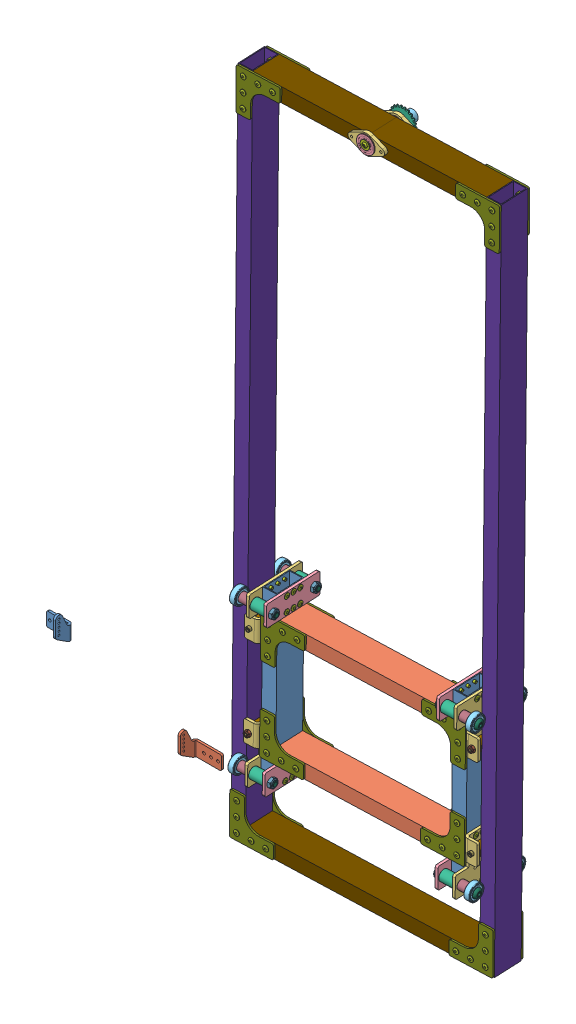
SolidWorks assembly Elevator Assembly, configuration Default. Lengths in mm.
Overall size (536.25 1232.63 399.07).
260 component instances, 26 part files, 13 mates.
Components (placement in the parent):
- Left Carriage Chain Mount-1: Left Carriage Chain Mount [Default] at (-1.4797 21.5105 53.1771) size (44.45 50.8 31.75)
- Right Carriage Chain Mount-1: Right Carriage Chain Mount [Default] at (172.2873 -143.217 -42.9173) size (50.8 50.8 31.75)
- am-3844a Example Single Stage Elevator Bearing Kit (1).STEP-1: am-3844a Example Single Stage Elevator Bearing Kit (1).STEP [Default] at (43.0927 -420.3455 -214.8461) x (0.998923 -0.01032 -0.045245) z (0.045242 -0.000545 0.998976) size (457.2 1219.2 116.33)
  - Example Single Corner Bearing Assembly R2.STEP-1: Example Single Corner Bearing Assembly R2.STEP [Default] at (14.8715 309.5253 9.4128) x (0 0 1) z (-1 0 0) size (112.43 88.9 74.91)
    - Large Bearing Block Plate R2.STEP-1: Large Bearing Block Plate R2.STEP [Default] at (-85.6128 70.3392 -35.9285) x (1 0 0) z (0 -1 0) size (101.6 24.99 88.9)
    - Small Bearing Block Plate R2.STEP-1: Small Bearing Block Plate R2.STEP [Default] at (-85.6128 70.3392 -66.091) x (1 0 0) z (0 -1 0) size (101.6 4.76 38.1)
    - 1614Z Bearing.STEP-1: 1614Z Bearing.STEP [Default] at (-74.6273 89.3892 -8.941) x (0.346238 -0.938147 0) z (0 0 1) size (28.57 28.57 9.53)
    - 1614Z Bearing.STEP-2: 1614Z Bearing.STEP [Default] at (5.0017 89.3892 -8.941) x (0.999932 0.011696 0) z (0 0 1) size (28.57 28.57 9.53)
    - AS75-18-64 Aluminum Spacer.STEP-1: AS75-18-64 Aluminum Spacer.STEP [Default] at (5.0017 89.3892 -35.9285) x (-0.078952 0.996878 0) z (-0.996878 -0.078952 0) size (19.05 25.4 19.05)
    - AS75-18-64 Aluminum Spacer.STEP-2: AS75-18-64 Aluminum Spacer.STEP [Default] at (-74.6273 89.3892 -61.3285) x (-0.205985 0.978555 0) z (0.978555 0.205985 0) size (19.05 25.4 19.05)
    - 187 pop rivet.STEP-1: 187 pop rivet.STEP [Default] at (-22.1128 102.0892 -41.707) x (0.970848 -0.239695 0) z (-0.239695 -0.970848 0) size (9.53 12.06 9.53)
    - 187 pop rivet.STEP-2: 187 pop rivet.STEP [Default] at (-22.1128 102.0892 -55.55) x (1 0 0) z (0 1 0) size (9.53 12.06 9.53)
    - 187 pop rivet.STEP-3: 187 pop rivet.STEP [Default] at (-34.8128 102.0892 -41.707) x (0.970848 -0.239695 0) z (-0.239695 -0.970848 0) size (9.53 12.06 9.53)
    - 187 pop rivet.STEP-4: 187 pop rivet.STEP [Default] at (-47.5128 102.0892 -41.707) x (0.970848 -0.239695 0) z (-0.239695 -0.970848 0) size (9.53 12.06 9.53)
    - 187 pop rivet.STEP-5: 187 pop rivet.STEP [Default] at (-22.1128 25.8892 -41.707) x (0.970848 -0.239695 0) z (-0.239695 -0.970848 0) size (9.53 12.06 9.53)
    - 187 pop rivet.STEP-6: 187 pop rivet.STEP [Default] at (-34.8128 25.8892 -41.707) x (0.970848 -0.239695 0) z (-0.239695 -0.970848 0) size (9.53 12.06 9.53)
    - 187 pop rivet.STEP-7: 187 pop rivet.STEP [Default] at (-47.5128 25.8892 -41.707) x (0.970848 -0.239695 0) z (-0.239695 -0.970848 0) size (9.53 12.06 9.53)
    - 187 pop rivet.STEP-8: 187 pop rivet.STEP [Default] at (-22.1128 76.6892 -55.55) x (1 0 0) z (0 1 0) size (9.53 12.06 9.53)
    - 187 pop rivet.STEP-9: 187 pop rivet.STEP [Default] at (-34.8128 102.0892 -55.55) x (1 0 0) z (0 1 0) size (9.53 12.06 9.53)
    - 187 pop rivet.STEP-10: 187 pop rivet.STEP [Default] at (-34.8128 76.6892 -55.55) x (1 0 0) z (0 1 0) size (9.53 12.06 9.53)
    - 187 pop rivet.STEP-11: 187 pop rivet.STEP [Default] at (-47.5128 102.0892 -55.55) x (1 0 0) z (0 1 0) size (9.53 12.06 9.53)
    - 187 pop rivet.STEP-12: 187 pop rivet.STEP [Default] at (-47.5128 76.6892 -55.55) x (1 0 0) z (0 1 0) size (9.53 12.06 9.53)
    - am-0602 .250 x .192 x 2.14 Brass Tube.STEP-1: am-0602 .250 x .192 x 2.14 Brass Tube.STEP [Default] at (-7.6348 38.5892 -20.0535) x (0 -0.358682 0.93346) z (-1 0 0) size (6.35 6.35 54.36)
    - 13RS075051 .750 x .260 x 1.00 Spacer.STEP-1: 13RS075051 .750 x .260 x 1.00 Spacer.STEP [Default] at (-60.2128 38.5892 -20.0535) x (0 -0.722855 0.691) z (0 0.691 0.722855) size (19.05 25.4 19.05)
    - 13RS075051 .750 x .260 x 1.00 Spacer.STEP-2: 13RS075051 .750 x .260 x 1.00 Spacer.STEP [Default] at (-34.8128 38.5892 -20.0535) x (0 -0.801304 -0.598258) z (0 -0.598258 0.801304) size (19.05 25.4 19.05)
    - 0.25 Flat Washer_Preferred Wide FW 0.25.STEP-1: 0.25 Flat Washer_Preferred Wide FW 0.25.STEP [Default] at (-60.2128 38.5892 -20.0535) x (1 0 0) z (0 -0.116572 0.993182) size (1.4 15.88 15.88)
    - 0.25 Flat Washer_Preferred Wide FW 0.25.STEP-2: 0.25 Flat Washer_Preferred Wide FW 0.25.STEP [Default] at (-8.0158 38.5892 -20.0535) size (1.4 15.88 15.88)
    - 10-32 Nylock Nut.STEP-1: 10-32 Nylock Nut.STEP [Default] at (-66.7533 38.5892 -20.0535) x (0 -0.097883 0.995198) z (-1 0 0) size (9.53 11.17 7.11)
    - SHCS 10-32 x 2.75_HX-SHCS 0.19-32x2.75x0.875-C.STEP-1: SHCS 10-32 x 2.75_HX-SHCS 0.19-32x2.75x0.875-C.STEP [Default] at (1.9537 38.5892 -20.0535) x (-1 0 0) z (0 -0.944703 0.327928) size (74.68 7.94 7.94)
    - AS62-18-44 Aluminum Spacer.STEP-1: AS62-18-44 Aluminum Spacer.STEP [Default] at (5.0017 89.3892 -13.7035) x (0.999229 -0.039261 0) z (0.039261 0.999229 0) size (15.88 17.46 15.88)
    - AS62-18-44 Aluminum Spacer.STEP-2: AS62-18-44 Aluminum Spacer.STEP [Default] at (-74.6273 89.3892 -13.7035) x (1 0 0) z (0 1 0) size (15.88 17.46 15.88)
    - 38-16 Nylock Jam Nut_90566A031.STEP-1: 38-16 Nylock Jam Nut_90566A031.STEP [Default] at (5.0017 89.3892 -66.091) x (1 0 0) z (0 1 0) size (14.29 6.75 16.5)
    - 38-16 Nylock Jam Nut_90566A031.STEP-2: 38-16 Nylock Jam Nut_90566A031.STEP [Default] at (-74.6273 89.3892 -66.091) x (1 0 0) z (0 1 0) size (14.29 6.75 16.5)
    - 91255A636_ALLOY STEEL BUTTON-HEAD SOCKET CAP SCREW_91255A636.STEP-1: 91255A636_ALLOY STEEL BUTTON-HEAD SOCKET CAP SCREW_91255A636.STEP [Default] at (-74.6273 89.3892 0.8761) size (16.66 16.66 74.91)
    - 91255A636_ALLOY STEEL BUTTON-HEAD SOCKET CAP SCREW_91255A636.STEP-2: 91255A636_ALLOY STEEL BUTTON-HEAD SOCKET CAP SCREW_91255A636.STEP [Default] at (5.0017 89.3892 0.8761) size (16.66 16.66 74.91)
  - Example Single Corner Bearing Assembly R2.STEP-2: Example Single Corner Bearing Assembly R2.STEP [Default] at (14.8715 221.6036 -60.2128) x (0 0 -1) z (-1 0 0) size (112.43 88.9 74.91)
    - Large Bearing Block Plate R2.STEP-1: Large Bearing Block Plate R2.STEP [Default] at (-85.6128 70.3392 -35.9285) x (1 0 0) z (0 -1 0) size (101.6 24.99 88.9)
    - Small Bearing Block Plate R2.STEP-1: Small Bearing Block Plate R2.STEP [Default] at (-85.6128 70.3392 -66.091) x (1 0 0) z (0 -1 0) size (101.6 4.76 38.1)
    - 1614Z Bearing.STEP-1: 1614Z Bearing.STEP [Default] at (-74.6273 89.3892 -8.941) x (0.346238 -0.938147 0) z (0 0 1) size (28.57 28.57 9.53)
    - 1614Z Bearing.STEP-2: 1614Z Bearing.STEP [Default] at (5.0017 89.3892 -8.941) x (0.999932 0.011696 0) z (0 0 1) size (28.57 28.57 9.53)
    - AS75-18-64 Aluminum Spacer.STEP-1: AS75-18-64 Aluminum Spacer.STEP [Default] at (5.0017 89.3892 -35.9285) x (-0.078952 0.996878 0) z (-0.996878 -0.078952 0) size (19.05 25.4 19.05)
    - AS75-18-64 Aluminum Spacer.STEP-2: AS75-18-64 Aluminum Spacer.STEP [Default] at (-74.6273 89.3892 -61.3285) x (-0.205985 0.978555 0) z (0.978555 0.205985 0) size (19.05 25.4 19.05)
    - 187 pop rivet.STEP-1: 187 pop rivet.STEP [Default] at (-22.1128 102.0892 -41.707) x (0.970848 -0.239695 0) z (-0.239695 -0.970848 0) size (9.53 12.06 9.53)
    - 187 pop rivet.STEP-2: 187 pop rivet.STEP [Default] at (-22.1128 102.0892 -55.55) x (1 0 0) z (0 1 0) size (9.53 12.06 9.53)
    - 187 pop rivet.STEP-3: 187 pop rivet.STEP [Default] at (-34.8128 102.0892 -41.707) x (0.970848 -0.239695 0) z (-0.239695 -0.970848 0) size (9.53 12.06 9.53)
    - 187 pop rivet.STEP-4: 187 pop rivet.STEP [Default] at (-47.5128 102.0892 -41.707) x (0.970848 -0.239695 0) z (-0.239695 -0.970848 0) size (9.53 12.06 9.53)
    - 187 pop rivet.STEP-5: 187 pop rivet.STEP [Default] at (-22.1128 25.8892 -41.707) x (0.970848 -0.239695 0) z (-0.239695 -0.970848 0) size (9.53 12.06 9.53)
    - 187 pop rivet.STEP-6: 187 pop rivet.STEP [Default] at (-34.8128 25.8892 -41.707) x (0.970848 -0.239695 0) z (-0.239695 -0.970848 0) size (9.53 12.06 9.53)
    - 187 pop rivet.STEP-7: 187 pop rivet.STEP [Default] at (-47.5128 25.8892 -41.707) x (0.970848 -0.239695 0) z (-0.239695 -0.970848 0) size (9.53 12.06 9.53)
    - 187 pop rivet.STEP-8: 187 pop rivet.STEP [Default] at (-22.1128 76.6892 -55.55) x (1 0 0) z (0 1 0) size (9.53 12.06 9.53)
    - 187 pop rivet.STEP-9: 187 pop rivet.STEP [Default] at (-34.8128 102.0892 -55.55) x (1 0 0) z (0 1 0) size (9.53 12.06 9.53)
    - 187 pop rivet.STEP-10: 187 pop rivet.STEP [Default] at (-34.8128 76.6892 -55.55) x (1 0 0) z (0 1 0) size (9.53 12.06 9.53)
    - 187 pop rivet.STEP-11: 187 pop rivet.STEP [Default] at (-47.5128 102.0892 -55.55) x (1 0 0) z (0 1 0) size (9.53 12.06 9.53)
    - 187 pop rivet.STEP-12: 187 pop rivet.STEP [Default] at (-47.5128 76.6892 -55.55) x (1 0 0) z (0 1 0) size (9.53 12.06 9.53)
    - am-0602 .250 x .192 x 2.14 Brass Tube.STEP-1: am-0602 .250 x .192 x 2.14 Brass Tube.STEP [Default] at (-7.6348 38.5892 -20.0535) x (0 -0.358682 0.93346) z (-1 0 0) size (6.35 6.35 54.36)
    - 13RS075051 .750 x .260 x 1.00 Spacer.STEP-1: 13RS075051 .750 x .260 x 1.00 Spacer.STEP [Default] at (-60.2128 38.5892 -20.0535) x (0 -0.722855 0.691) z (0 0.691 0.722855) size (19.05 25.4 19.05)
    - 13RS075051 .750 x .260 x 1.00 Spacer.STEP-2: 13RS075051 .750 x .260 x 1.00 Spacer.STEP [Default] at (-34.8128 38.5892 -20.0535) x (0 -0.801304 -0.598258) z (0 -0.598258 0.801304) size (19.05 25.4 19.05)
    - 0.25 Flat Washer_Preferred Wide FW 0.25.STEP-1: 0.25 Flat Washer_Preferred Wide FW 0.25.STEP [Default] at (-60.2128 38.5892 -20.0535) x (1 0 0) z (0 -0.116572 0.993182) size (1.4 15.88 15.88)
    - 0.25 Flat Washer_Preferred Wide FW 0.25.STEP-2: 0.25 Flat Washer_Preferred Wide FW 0.25.STEP [Default] at (-8.0158 38.5892 -20.0535) size (1.4 15.88 15.88)
    - 10-32 Nylock Nut.STEP-1: 10-32 Nylock Nut.STEP [Default] at (-66.7533 38.5892 -20.0535) x (0 -0.097883 0.995198) z (-1 0 0) size (9.53 11.17 7.11)
    - SHCS 10-32 x 2.75_HX-SHCS 0.19-32x2.75x0.875-C.STEP-1: SHCS 10-32 x 2.75_HX-SHCS 0.19-32x2.75x0.875-C.STEP [Default] at (1.9537 38.5892 -20.0535) x (-1 0 0) z (0 -0.944703 0.327928) size (74.68 7.94 7.94)
    - AS62-18-44 Aluminum Spacer.STEP-1: AS62-18-44 Aluminum Spacer.STEP [Default] at (5.0017 89.3892 -13.7035) x (0.999229 -0.039261 0) z (0.039261 0.999229 0) size (15.88 17.46 15.88)
    - AS62-18-44 Aluminum Spacer.STEP-2: AS62-18-44 Aluminum Spacer.STEP [Default] at (-74.6273 89.3892 -13.7035) x (1 0 0) z (0 1 0) size (15.88 17.46 15.88)
    - 38-16 Nylock Jam Nut_90566A031.STEP-1: 38-16 Nylock Jam Nut_90566A031.STEP [Default] at (5.0017 89.3892 -66.091) x (1 0 0) z (0 1 0) size (14.29 6.75 16.5)
    - 38-16 Nylock Jam Nut_90566A031.STEP-2: 38-16 Nylock Jam Nut_90566A031.STEP [Default] at (-74.6273 89.3892 -66.091) x (1 0 0) z (0 1 0) size (14.29 6.75 16.5)
    - 91255A636_ALLOY STEEL BUTTON-HEAD SOCKET CAP SCREW_91255A636.STEP-1: 91255A636_ALLOY STEEL BUTTON-HEAD SOCKET CAP SCREW_91255A636.STEP [Default] at (-74.6273 89.3892 0.8761) size (16.66 16.66 74.91)
    - 91255A636_ALLOY STEEL BUTTON-HEAD SOCKET CAP SCREW_91255A636.STEP-2: 91255A636_ALLOY STEEL BUTTON-HEAD SOCKET CAP SCREW_91255A636.STEP [Default] at (5.0017 89.3892 0.8761) size (16.66 16.66 74.91)
  - Example Single Corner Bearing Assembly R2.STEP-3: Example Single Corner Bearing Assembly R2.STEP [Default] at (442.3285 309.5253 -60.2128) x (0 0 -1) z (1 0 0) size (112.43 88.9 74.91)
    - Large Bearing Block Plate R2.STEP-1: Large Bearing Block Plate R2.STEP [Default] at (-85.6128 70.3392 -35.9285) x (1 0 0) z (0 -1 0) size (101.6 24.99 88.9)
    - Small Bearing Block Plate R2.STEP-1: Small Bearing Block Plate R2.STEP [Default] at (-85.6128 70.3392 -66.091) x (1 0 0) z (0 -1 0) size (101.6 4.76 38.1)
    - 1614Z Bearing.STEP-1: 1614Z Bearing.STEP [Default] at (-74.6273 89.3892 -8.941) x (0.346238 -0.938147 0) z (0 0 1) size (28.57 28.57 9.53)
    - 1614Z Bearing.STEP-2: 1614Z Bearing.STEP [Default] at (5.0017 89.3892 -8.941) x (0.999932 0.011696 0) z (0 0 1) size (28.57 28.57 9.53)
    - AS75-18-64 Aluminum Spacer.STEP-1: AS75-18-64 Aluminum Spacer.STEP [Default] at (5.0017 89.3892 -35.9285) x (-0.078952 0.996878 0) z (-0.996878 -0.078952 0) size (19.05 25.4 19.05)
    - AS75-18-64 Aluminum Spacer.STEP-2: AS75-18-64 Aluminum Spacer.STEP [Default] at (-74.6273 89.3892 -61.3285) x (-0.205985 0.978555 0) z (0.978555 0.205985 0) size (19.05 25.4 19.05)
    - 187 pop rivet.STEP-1: 187 pop rivet.STEP [Default] at (-22.1128 102.0892 -41.707) x (0.970848 -0.239695 0) z (-0.239695 -0.970848 0) size (9.53 12.06 9.53)
    - 187 pop rivet.STEP-2: 187 pop rivet.STEP [Default] at (-22.1128 102.0892 -55.55) x (1 0 0) z (0 1 0) size (9.53 12.06 9.53)
    - 187 pop rivet.STEP-3: 187 pop rivet.STEP [Default] at (-34.8128 102.0892 -41.707) x (0.970848 -0.239695 0) z (-0.239695 -0.970848 0) size (9.53 12.06 9.53)
    - 187 pop rivet.STEP-4: 187 pop rivet.STEP [Default] at (-47.5128 102.0892 -41.707) x (0.970848 -0.239695 0) z (-0.239695 -0.970848 0) size (9.53 12.06 9.53)
    - 187 pop rivet.STEP-5: 187 pop rivet.STEP [Default] at (-22.1128 25.8892 -41.707) x (0.970848 -0.239695 0) z (-0.239695 -0.970848 0) size (9.53 12.06 9.53)
    - 187 pop rivet.STEP-6: 187 pop rivet.STEP [Default] at (-34.8128 25.8892 -41.707) x (0.970848 -0.239695 0) z (-0.239695 -0.970848 0) size (9.53 12.06 9.53)
    - 187 pop rivet.STEP-7: 187 pop rivet.STEP [Default] at (-47.5128 25.8892 -41.707) x (0.970848 -0.239695 0) z (-0.239695 -0.970848 0) size (9.53 12.06 9.53)
    - 187 pop rivet.STEP-8: 187 pop rivet.STEP [Default] at (-22.1128 76.6892 -55.55) x (1 0 0) z (0 1 0) size (9.53 12.06 9.53)
    - 187 pop rivet.STEP-9: 187 pop rivet.STEP [Default] at (-34.8128 102.0892 -55.55) x (1 0 0) z (0 1 0) size (9.53 12.06 9.53)
    - 187 pop rivet.STEP-10: 187 pop rivet.STEP [Default] at (-34.8128 76.6892 -55.55) x (1 0 0) z (0 1 0) size (9.53 12.06 9.53)
    - 187 pop rivet.STEP-11: 187 pop rivet.STEP [Default] at (-47.5128 102.0892 -55.55) x (1 0 0) z (0 1 0) size (9.53 12.06 9.53)
    - 187 pop rivet.STEP-12: 187 pop rivet.STEP [Default] at (-47.5128 76.6892 -55.55) x (1 0 0) z (0 1 0) size (9.53 12.06 9.53)
    - am-0602 .250 x .192 x 2.14 Brass Tube.STEP-1: am-0602 .250 x .192 x 2.14 Brass Tube.STEP [Default] at (-7.6348 38.5892 -20.0535) x (0 -0.358682 0.93346) z (-1 0 0) size (6.35 6.35 54.36)
    - 13RS075051 .750 x .260 x 1.00 Spacer.STEP-1: 13RS075051 .750 x .260 x 1.00 Spacer.STEP [Default] at (-60.2128 38.5892 -20.0535) x (0 -0.722855 0.691) z (0 0.691 0.722855) size (19.05 25.4 19.05)
    - 13RS075051 .750 x .260 x 1.00 Spacer.STEP-2: 13RS075051 .750 x .260 x 1.00 Spacer.STEP [Default] at (-34.8128 38.5892 -20.0535) x (0 -0.801304 -0.598258) z (0 -0.598258 0.801304) size (19.05 25.4 19.05)
    - 0.25 Flat Washer_Preferred Wide FW 0.25.STEP-1: 0.25 Flat Washer_Preferred Wide FW 0.25.STEP [Default] at (-60.2128 38.5892 -20.0535) x (1 0 0) z (0 -0.116572 0.993182) size (1.4 15.88 15.88)
    - 0.25 Flat Washer_Preferred Wide FW 0.25.STEP-2: 0.25 Flat Washer_Preferred Wide FW 0.25.STEP [Default] at (-8.0158 38.5892 -20.0535) size (1.4 15.88 15.88)
    - 10-32 Nylock Nut.STEP-1: 10-32 Nylock Nut.STEP [Default] at (-66.7533 38.5892 -20.0535) x (0 -0.097883 0.995198) z (-1 0 0) size (9.53 11.17 7.11)
    - SHCS 10-32 x 2.75_HX-SHCS 0.19-32x2.75x0.875-C.STEP-1: SHCS 10-32 x 2.75_HX-SHCS 0.19-32x2.75x0.875-C.STEP [Default] at (1.9537 38.5892 -20.0535) x (-1 0 0) z (0 -0.944703 0.327928) size (74.68 7.94 7.94)
    - AS62-18-44 Aluminum Spacer.STEP-1: AS62-18-44 Aluminum Spacer.STEP [Default] at (5.0017 89.3892 -13.7035) x (0.999229 -0.039261 0) z (0.039261 0.999229 0) size (15.88 17.46 15.88)
    - AS62-18-44 Aluminum Spacer.STEP-2: AS62-18-44 Aluminum Spacer.STEP [Default] at (-74.6273 89.3892 -13.7035) x (1 0 0) z (0 1 0) size (15.88 17.46 15.88)
    - 38-16 Nylock Jam Nut_90566A031.STEP-1: 38-16 Nylock Jam Nut_90566A031.STEP [Default] at (5.0017 89.3892 -66.091) x (1 0 0) z (0 1 0) size (14.29 6.75 16.5)
    - 38-16 Nylock Jam Nut_90566A031.STEP-2: 38-16 Nylock Jam Nut_90566A031.STEP [Default] at (-74.6273 89.3892 -66.091) x (1 0 0) z (0 1 0) size (14.29 6.75 16.5)
    - 91255A636_ALLOY STEEL BUTTON-HEAD SOCKET CAP SCREW_91255A636.STEP-1: 91255A636_ALLOY STEEL BUTTON-HEAD SOCKET CAP SCREW_91255A636.STEP [Default] at (-74.6273 89.3892 0.8761) size (16.66 16.66 74.91)
    - 91255A636_ALLOY STEEL BUTTON-HEAD SOCKET CAP SCREW_91255A636.STEP-2: 91255A636_ALLOY STEEL BUTTON-HEAD SOCKET CAP SCREW_91255A636.STEP [Default] at (5.0017 89.3892 0.8761) size (16.66 16.66 74.91)
  - Example Single Corner Bearing Assembly R2.STEP-4: Example Single Corner Bearing Assembly R2.STEP [Default] at (442.3285 221.6036 9.4128) x (0 0 1) z (1 0 0) size (112.43 88.9 74.91)
    - Large Bearing Block Plate R2.STEP-1: Large Bearing Block Plate R2.STEP [Default] at (-85.6128 70.3392 -35.9285) x (1 0 0) z (0 -1 0) size (101.6 24.99 88.9)
    - Small Bearing Block Plate R2.STEP-1: Small Bearing Block Plate R2.STEP [Default] at (-85.6128 70.3392 -66.091) x (1 0 0) z (0 -1 0) size (101.6 4.76 38.1)
    - 1614Z Bearing.STEP-1: 1614Z Bearing.STEP [Default] at (-74.6273 89.3892 -8.941) x (0.346238 -0.938147 0) z (0 0 1) size (28.57 28.57 9.53)
    - 1614Z Bearing.STEP-2: 1614Z Bearing.STEP [Default] at (5.0017 89.3892 -8.941) x (0.999932 0.011696 0) z (0 0 1) size (28.57 28.57 9.53)
    - AS75-18-64 Aluminum Spacer.STEP-1: AS75-18-64 Aluminum Spacer.STEP [Default] at (5.0017 89.3892 -35.9285) x (-0.078952 0.996878 0) z (-0.996878 -0.078952 0) size (19.05 25.4 19.05)
    - AS75-18-64 Aluminum Spacer.STEP-2: AS75-18-64 Aluminum Spacer.STEP [Default] at (-74.6273 89.3892 -61.3285) x (-0.205985 0.978555 0) z (0.978555 0.205985 0) size (19.05 25.4 19.05)
    - 187 pop rivet.STEP-1: 187 pop rivet.STEP [Default] at (-22.1128 102.0892 -41.707) x (0.970848 -0.239695 0) z (-0.239695 -0.970848 0) size (9.53 12.06 9.53)
    - 187 pop rivet.STEP-2: 187 pop rivet.STEP [Default] at (-22.1128 102.0892 -55.55) x (1 0 0) z (0 1 0) size (9.53 12.06 9.53)
    - 187 pop rivet.STEP-3: 187 pop rivet.STEP [Default] at (-34.8128 102.0892 -41.707) x (0.970848 -0.239695 0) z (-0.239695 -0.970848 0) size (9.53 12.06 9.53)
    - 187 pop rivet.STEP-4: 187 pop rivet.STEP [Default] at (-47.5128 102.0892 -41.707) x (0.970848 -0.239695 0) z (-0.239695 -0.970848 0) size (9.53 12.06 9.53)
    - 187 pop rivet.STEP-5: 187 pop rivet.STEP [Default] at (-22.1128 25.8892 -41.707) x (0.970848 -0.239695 0) z (-0.239695 -0.970848 0) size (9.53 12.06 9.53)
    - 187 pop rivet.STEP-6: 187 pop rivet.STEP [Default] at (-34.8128 25.8892 -41.707) x (0.970848 -0.239695 0) z (-0.239695 -0.970848 0) size (9.53 12.06 9.53)
    - 187 pop rivet.STEP-7: 187 pop rivet.STEP [Default] at (-47.5128 25.8892 -41.707) x (0.970848 -0.239695 0) z (-0.239695 -0.970848 0) size (9.53 12.06 9.53)
    - 187 pop rivet.STEP-8: 187 pop rivet.STEP [Default] at (-22.1128 76.6892 -55.55) x (1 0 0) z (0 1 0) size (9.53 12.06 9.53)
    - 187 pop rivet.STEP-9: 187 pop rivet.STEP [Default] at (-34.8128 102.0892 -55.55) x (1 0 0) z (0 1 0) size (9.53 12.06 9.53)
    - 187 pop rivet.STEP-10: 187 pop rivet.STEP [Default] at (-34.8128 76.6892 -55.55) x (1 0 0) z (0 1 0) size (9.53 12.06 9.53)
    - 187 pop rivet.STEP-11: 187 pop rivet.STEP [Default] at (-47.5128 102.0892 -55.55) x (1 0 0) z (0 1 0) size (9.53 12.06 9.53)
    - 187 pop rivet.STEP-12: 187 pop rivet.STEP [Default] at (-47.5128 76.6892 -55.55) x (1 0 0) z (0 1 0) size (9.53 12.06 9.53)
    - am-0602 .250 x .192 x 2.14 Brass Tube.STEP-1: am-0602 .250 x .192 x 2.14 Brass Tube.STEP [Default] at (-7.6348 38.5892 -20.0535) x (0 -0.358682 0.93346) z (-1 0 0) size (6.35 6.35 54.36)
    - 13RS075051 .750 x .260 x 1.00 Spacer.STEP-1: 13RS075051 .750 x .260 x 1.00 Spacer.STEP [Default] at (-60.2128 38.5892 -20.0535) x (0 -0.722855 0.691) z (0 0.691 0.722855) size (19.05 25.4 19.05)
    - 13RS075051 .750 x .260 x 1.00 Spacer.STEP-2: 13RS075051 .750 x .260 x 1.00 Spacer.STEP [Default] at (-34.8128 38.5892 -20.0535) x (0 -0.801304 -0.598258) z (0 -0.598258 0.801304) size (19.05 25.4 19.05)
    - 0.25 Flat Washer_Preferred Wide FW 0.25.STEP-1: 0.25 Flat Washer_Preferred Wide FW 0.25.STEP [Default] at (-60.2128 38.5892 -20.0535) x (1 0 0) z (0 -0.116572 0.993182) size (1.4 15.88 15.88)
    - 0.25 Flat Washer_Preferred Wide FW 0.25.STEP-2: 0.25 Flat Washer_Preferred Wide FW 0.25.STEP [Default] at (-8.0158 38.5892 -20.0535) size (1.4 15.88 15.88)
    - 10-32 Nylock Nut.STEP-1: 10-32 Nylock Nut.STEP [Default] at (-66.7533 38.5892 -20.0535) x (0 -0.097883 0.995198) z (-1 0 0) size (9.53 11.17 7.11)
    - SHCS 10-32 x 2.75_HX-SHCS 0.19-32x2.75x0.875-C.STEP-1: SHCS 10-32 x 2.75_HX-SHCS 0.19-32x2.75x0.875-C.STEP [Default] at (1.9537 38.5892 -20.0535) x (-1 0 0) z (0 -0.944703 0.327928) size (74.68 7.94 7.94)
    - AS62-18-44 Aluminum Spacer.STEP-1: AS62-18-44 Aluminum Spacer.STEP [Default] at (5.0017 89.3892 -13.7035) x (0.999229 -0.039261 0) z (0.039261 0.999229 0) size (15.88 17.46 15.88)
    - AS62-18-44 Aluminum Spacer.STEP-2: AS62-18-44 Aluminum Spacer.STEP [Default] at (-74.6273 89.3892 -13.7035) x (1 0 0) z (0 1 0) size (15.88 17.46 15.88)
    - 38-16 Nylock Jam Nut_90566A031.STEP-1: 38-16 Nylock Jam Nut_90566A031.STEP [Default] at (5.0017 89.3892 -66.091) x (1 0 0) z (0 1 0) size (14.29 6.75 16.5)
    - 38-16 Nylock Jam Nut_90566A031.STEP-2: 38-16 Nylock Jam Nut_90566A031.STEP [Default] at (-74.6273 89.3892 -66.091) x (1 0 0) z (0 1 0) size (14.29 6.75 16.5)
    - 91255A636_ALLOY STEEL BUTTON-HEAD SOCKET CAP SCREW_91255A636.STEP-1: 91255A636_ALLOY STEEL BUTTON-HEAD SOCKET CAP SCREW_91255A636.STEP [Default] at (-74.6273 89.3892 0.8761) size (16.66 16.66 74.91)
    - 91255A636_ALLOY STEEL BUTTON-HEAD SOCKET CAP SCREW_91255A636.STEP-2: 91255A636_ALLOY STEEL BUTTON-HEAD SOCKET CAP SCREW_91255A636.STEP [Default] at (5.0017 89.3892 0.8761) size (16.66 16.66 74.91)
  - am-3860 90 Gusset with Rivets.STEP-1: am-3860 90 Gusset with Rivets.STEP [Default] at (379.0872 1079.1222 -32.0758) x (0 -1 0) z (1 0 0) size (76.2 12.06 76.2)
    - am-3860 90 Gusset.STEP-1: am-3860 90 Gusset.STEP [Default] at (-140.0778 18.7242 78.1128) size (76.2 3.17 76.2)
    - 187 pop rivet.STEP-1: 187 pop rivet.STEP [Default] at (-127.3778 11.3582 65.4128) size (9.53 12.06 9.53)
    - 187 pop rivet.STEP-2: 187 pop rivet.STEP [Default] at (-101.9778 11.3582 65.4128) size (9.53 12.06 9.53)
    - 187 pop rivet.STEP-3: 187 pop rivet.STEP [Default] at (-76.5778 11.3582 65.4128) size (9.53 12.06 9.53)
    - 187 pop rivet.STEP-4: 187 pop rivet.STEP [Default] at (-127.3778 11.3582 40.0128) size (9.53 12.06 9.53)
    - 187 pop rivet.STEP-5: 187 pop rivet.STEP [Default] at (-127.3778 11.3582 14.6128) size (9.53 12.06 9.53)
  - am-3860 90 Gusset with Rivets.STEP-2: am-3860 90 Gusset with Rivets.STEP [Default] at (317.1222 1141.0872 -18.7242) x (-1 0 0) z (0 1 0) size (76.2 12.06 76.2)
    - am-3860 90 Gusset.STEP-1: am-3860 90 Gusset.STEP [Default] at (-140.0778 18.7242 78.1128) size (76.2 3.17 76.2)
    - 187 pop rivet.STEP-1: 187 pop rivet.STEP [Default] at (-127.3778 11.3582 65.4128) size (9.53 12.06 9.53)
    - 187 pop rivet.STEP-2: 187 pop rivet.STEP [Default] at (-101.9778 11.3582 65.4128) size (9.53 12.06 9.53)
    - 187 pop rivet.STEP-3: 187 pop rivet.STEP [Default] at (-76.5778 11.3582 65.4128) size (9.53 12.06 9.53)
    - 187 pop rivet.STEP-4: 187 pop rivet.STEP [Default] at (-127.3778 11.3582 40.0128) size (9.53 12.06 9.53)
    - 187 pop rivet.STEP-5: 187 pop rivet.STEP [Default] at (-127.3778 11.3582 14.6128) size (9.53 12.06 9.53)
  - am-3860 90 Gusset with Rivets.STEP-3: am-3860 90 Gusset with Rivets.STEP [Default] at (78.1128 1079.1222 -18.7242) x (0 -1 0) z (-1 0 0) size (76.2 12.06 76.2)
    - am-3860 90 Gusset.STEP-1: am-3860 90 Gusset.STEP [Default] at (-140.0778 18.7242 78.1128) size (76.2 3.17 76.2)
    - 187 pop rivet.STEP-1: 187 pop rivet.STEP [Default] at (-127.3778 11.3582 65.4128) size (9.53 12.06 9.53)
    - 187 pop rivet.STEP-2: 187 pop rivet.STEP [Default] at (-101.9778 11.3582 65.4128) size (9.53 12.06 9.53)
    - 187 pop rivet.STEP-3: 187 pop rivet.STEP [Default] at (-76.5778 11.3582 65.4128) size (9.53 12.06 9.53)
    - 187 pop rivet.STEP-4: 187 pop rivet.STEP [Default] at (-127.3778 11.3582 40.0128) size (9.53 12.06 9.53)
    - 187 pop rivet.STEP-5: 187 pop rivet.STEP [Default] at (-127.3778 11.3582 14.6128) size (9.53 12.06 9.53)
  - am-3860 90 Gusset with Rivets.STEP-4: am-3860 90 Gusset with Rivets.STEP [Default] at (140.0778 1141.0872 -32.0758) x (1 0 0) z (0 1 0) size (76.2 12.06 76.2)
    - am-3860 90 Gusset.STEP-1: am-3860 90 Gusset.STEP [Default] at (-140.0778 18.7242 78.1128) size (76.2 3.17 76.2)
    - 187 pop rivet.STEP-1: 187 pop rivet.STEP [Default] at (-127.3778 11.3582 65.4128) size (9.53 12.06 9.53)
    - 187 pop rivet.STEP-2: 187 pop rivet.STEP [Default] at (-101.9778 11.3582 65.4128) size (9.53 12.06 9.53)
    - 187 pop rivet.STEP-3: 187 pop rivet.STEP [Default] at (-76.5778 11.3582 65.4128) size (9.53 12.06 9.53)
    - 187 pop rivet.STEP-4: 187 pop rivet.STEP [Default] at (-127.3778 11.3582 40.0128) size (9.53 12.06 9.53)
    - 187 pop rivet.STEP-5: 187 pop rivet.STEP [Default] at (-127.3778 11.3582 14.6128) size (9.53 12.06 9.53)
  - am-3860 90 Gusset with Rivets.STEP-5: am-3860 90 Gusset with Rivets.STEP [Default] at (317.1222 78.1128 -32.0758) x (-1 0 0) z (0 -1 0) size (76.2 12.06 76.2)
    - am-3860 90 Gusset.STEP-1: am-3860 90 Gusset.STEP [Default] at (-140.0778 18.7242 78.1128) size (76.2 3.17 76.2)
    - 187 pop rivet.STEP-1: 187 pop rivet.STEP [Default] at (-127.3778 11.3582 65.4128) size (9.53 12.06 9.53)
    - 187 pop rivet.STEP-2: 187 pop rivet.STEP [Default] at (-101.9778 11.3582 65.4128) size (9.53 12.06 9.53)
    - 187 pop rivet.STEP-3: 187 pop rivet.STEP [Default] at (-76.5778 11.3582 65.4128) size (9.53 12.06 9.53)
    - 187 pop rivet.STEP-4: 187 pop rivet.STEP [Default] at (-127.3778 11.3582 40.0128) size (9.53 12.06 9.53)
    - 187 pop rivet.STEP-5: 187 pop rivet.STEP [Default] at (-127.3778 11.3582 14.6128) size (9.53 12.06 9.53)
  - am-3860 90 Gusset with Rivets.STEP-6: am-3860 90 Gusset with Rivets.STEP [Default] at (379.0872 140.0778 -18.7242) x (0 1 0) z (1 0 0) size (76.2 12.06 76.2)
    - am-3860 90 Gusset.STEP-1: am-3860 90 Gusset.STEP [Default] at (-140.0778 18.7242 78.1128) size (76.2 3.17 76.2)
    - 187 pop rivet.STEP-1: 187 pop rivet.STEP [Default] at (-127.3778 11.3582 65.4128) size (9.53 12.06 9.53)
    - 187 pop rivet.STEP-2: 187 pop rivet.STEP [Default] at (-101.9778 11.3582 65.4128) size (9.53 12.06 9.53)
    - 187 pop rivet.STEP-3: 187 pop rivet.STEP [Default] at (-76.5778 11.3582 65.4128) size (9.53 12.06 9.53)
    - 187 pop rivet.STEP-4: 187 pop rivet.STEP [Default] at (-127.3778 11.3582 40.0128) size (9.53 12.06 9.53)
    - 187 pop rivet.STEP-5: 187 pop rivet.STEP [Default] at (-127.3778 11.3582 14.6128) size (9.53 12.06 9.53)
  - am-3860 90 Gusset with Rivets.STEP-7: am-3860 90 Gusset with Rivets.STEP [Default] at (78.1128 140.0778 -32.0758) x (0 1 0) z (-1 0 0) size (76.2 12.06 76.2)
    - am-3860 90 Gusset.STEP-1: am-3860 90 Gusset.STEP [Default] at (-140.0778 18.7242 78.1128) size (76.2 3.17 76.2)
    - 187 pop rivet.STEP-1: 187 pop rivet.STEP [Default] at (-127.3778 11.3582 65.4128) size (9.53 12.06 9.53)
    - 187 pop rivet.STEP-2: 187 pop rivet.STEP [Default] at (-101.9778 11.3582 65.4128) size (9.53 12.06 9.53)
    - 187 pop rivet.STEP-3: 187 pop rivet.STEP [Default] at (-76.5778 11.3582 65.4128) size (9.53 12.06 9.53)
    - 187 pop rivet.STEP-4: 187 pop rivet.STEP [Default] at (-127.3778 11.3582 40.0128) size (9.53 12.06 9.53)
    - 187 pop rivet.STEP-5: 187 pop rivet.STEP [Default] at (-127.3778 11.3582 14.6128) size (9.53 12.06 9.53)
  - am-3860 90 Gusset with Rivets.STEP-8: am-3860 90 Gusset with Rivets.STEP [Default] at (140.0778 78.1128 -18.7242) x (1 0 0) z (0 -1 0) size (76.2 12.06 76.2)
    - am-3860 90 Gusset.STEP-1: am-3860 90 Gusset.STEP [Default] at (-140.0778 18.7242 78.1128) size (76.2 3.17 76.2)
    - 187 pop rivet.STEP-1: 187 pop rivet.STEP [Default] at (-127.3778 11.3582 65.4128) size (9.53 12.06 9.53)
    - 187 pop rivet.STEP-2: 187 pop rivet.STEP [Default] at (-101.9778 11.3582 65.4128) size (9.53 12.06 9.53)
    - 187 pop rivet.STEP-3: 187 pop rivet.STEP [Default] at (-76.5778 11.3582 65.4128) size (9.53 12.06 9.53)
    - 187 pop rivet.STEP-4: 187 pop rivet.STEP [Default] at (-127.3778 11.3582 40.0128) size (9.53 12.06 9.53)
    - 187 pop rivet.STEP-5: 187 pop rivet.STEP [Default] at (-127.3778 11.3582 14.6128) size (9.53 12.06 9.53)
  - am-3860 90 Gusset with Rivets.STEP-9: am-3860 90 Gusset with Rivets.STEP [Default] at (128.9128 291.3422 -32.0758) x (0 1 0) z (-1 0 0) size (76.2 12.06 76.2)
    - am-3860 90 Gusset.STEP-1: am-3860 90 Gusset.STEP [Default] at (-140.0778 18.7242 78.1128) size (76.2 3.17 76.2)
    - 187 pop rivet.STEP-1: 187 pop rivet.STEP [Default] at (-127.3778 11.3582 65.4128) size (9.53 12.06 9.53)
    - 187 pop rivet.STEP-2: 187 pop rivet.STEP [Default] at (-101.9778 11.3582 65.4128) size (9.53 12.06 9.53)
    - 187 pop rivet.STEP-3: 187 pop rivet.STEP [Default] at (-76.5778 11.3582 65.4128) size (9.53 12.06 9.53)
    - 187 pop rivet.STEP-4: 187 pop rivet.STEP [Default] at (-127.3778 11.3582 40.0128) size (9.53 12.06 9.53)
    - 187 pop rivet.STEP-5: 187 pop rivet.STEP [Default] at (-127.3778 11.3582 14.6128) size (9.53 12.06 9.53)
  - am-3860 90 Gusset with Rivets.STEP-10: am-3860 90 Gusset with Rivets.STEP [Default] at (190.8778 229.3772 -18.7242) x (1 0 0) z (0 -1 0) size (76.2 12.06 76.2)
    - am-3860 90 Gusset.STEP-1: am-3860 90 Gusset.STEP [Default] at (-140.0778 18.7242 78.1128) size (76.2 3.17 76.2)
    - 187 pop rivet.STEP-1: 187 pop rivet.STEP [Default] at (-127.3778 11.3582 65.4128) size (9.53 12.06 9.53)
    - 187 pop rivet.STEP-2: 187 pop rivet.STEP [Default] at (-101.9778 11.3582 65.4128) size (9.53 12.06 9.53)
    - 187 pop rivet.STEP-3: 187 pop rivet.STEP [Default] at (-76.5778 11.3582 65.4128) size (9.53 12.06 9.53)
    - 187 pop rivet.STEP-4: 187 pop rivet.STEP [Default] at (-127.3778 11.3582 40.0128) size (9.53 12.06 9.53)
    - 187 pop rivet.STEP-5: 187 pop rivet.STEP [Default] at (-127.3778 11.3582 14.6128) size (9.53 12.06 9.53)
  - am-3860 90 Gusset with Rivets.STEP-11: am-3860 90 Gusset with Rivets.STEP [Default] at (266.3222 229.3772 -32.0758) x (-1 0 0) z (0 -1 0) size (76.2 12.06 76.2)
    - am-3860 90 Gusset.STEP-1: am-3860 90 Gusset.STEP [Default] at (-140.0778 18.7242 78.1128) size (76.2 3.17 76.2)
    - 187 pop rivet.STEP-1: 187 pop rivet.STEP [Default] at (-127.3778 11.3582 65.4128) size (9.53 12.06 9.53)
    - 187 pop rivet.STEP-2: 187 pop rivet.STEP [Default] at (-101.9778 11.3582 65.4128) size (9.53 12.06 9.53)
    - 187 pop rivet.STEP-3: 187 pop rivet.STEP [Default] at (-76.5778 11.3582 65.4128) size (9.53 12.06 9.53)
    - 187 pop rivet.STEP-4: 187 pop rivet.STEP [Default] at (-127.3778 11.3582 40.0128) size (9.53 12.06 9.53)
    - 187 pop rivet.STEP-5: 187 pop rivet.STEP [Default] at (-127.3778 11.3582 14.6128) size (9.53 12.06 9.53)
  - am-3860 90 Gusset with Rivets.STEP-12: am-3860 90 Gusset with Rivets.STEP [Default] at (328.2872 239.7867 -32.0758) x (0 -1 0) z (1 0 0) size (76.2 12.06 76.2)
    - am-3860 90 Gusset.STEP-1: am-3860 90 Gusset.STEP [Default] at (-140.0778 18.7242 78.1128) size (76.2 3.17 76.2)
    - 187 pop rivet.STEP-1: 187 pop rivet.STEP [Default] at (-127.3778 11.3582 65.4128) size (9.53 12.06 9.53)
    - 187 pop rivet.STEP-2: 187 pop rivet.STEP [Default] at (-101.9778 11.3582 65.4128) size (9.53 12.06 9.53)
    - 187 pop rivet.STEP-3: 187 pop rivet.STEP [Default] at (-76.5778 11.3582 65.4128) size (9.53 12.06 9.53)
    - 187 pop rivet.STEP-4: 187 pop rivet.STEP [Default] at (-127.3778 11.3582 40.0128) size (9.53 12.06 9.53)
    - 187 pop rivet.STEP-5: 187 pop rivet.STEP [Default] at (-127.3778 11.3582 14.6128) size (9.53 12.06 9.53)
  - am-3860 90 Gusset with Rivets.STEP-13: am-3860 90 Gusset with Rivets.STEP [Default] at (128.9128 239.7867 -18.7242) x (0 -1 0) z (-1 0 0) size (76.2 12.06 76.2)
    - am-3860 90 Gusset.STEP-1: am-3860 90 Gusset.STEP [Default] at (-140.0778 18.7242 78.1128) size (76.2 3.17 76.2)
    - 187 pop rivet.STEP-1: 187 pop rivet.STEP [Default] at (-127.3778 11.3582 65.4128) size (9.53 12.06 9.53)
    - 187 pop rivet.STEP-2: 187 pop rivet.STEP [Default] at (-101.9778 11.3582 65.4128) size (9.53 12.06 9.53)
    - 187 pop rivet.STEP-3: 187 pop rivet.STEP [Default] at (-76.5778 11.3582 65.4128) size (9.53 12.06 9.53)
    - 187 pop rivet.STEP-4: 187 pop rivet.STEP [Default] at (-127.3778 11.3582 40.0128) size (9.53 12.06 9.53)
    - 187 pop rivet.STEP-5: 187 pop rivet.STEP [Default] at (-127.3778 11.3582 14.6128) size (9.53 12.06 9.53)
  - am-3860 90 Gusset with Rivets.STEP-14: am-3860 90 Gusset with Rivets.STEP [Default] at (190.8778 301.7516 -32.0758) x (1 0 0) z (0 1 0) size (76.2 12.06 76.2)
    - am-3860 90 Gusset.STEP-1: am-3860 90 Gusset.STEP [Default] at (-140.0778 18.7242 78.1128) size (76.2 3.17 76.2)
    - 187 pop rivet.STEP-1: 187 pop rivet.STEP [Default] at (-127.3778 11.3582 65.4128) size (9.53 12.06 9.53)
    - 187 pop rivet.STEP-2: 187 pop rivet.STEP [Default] at (-101.9778 11.3582 65.4128) size (9.53 12.06 9.53)
    - 187 pop rivet.STEP-3: 187 pop rivet.STEP [Default] at (-76.5778 11.3582 65.4128) size (9.53 12.06 9.53)
    - 187 pop rivet.STEP-4: 187 pop rivet.STEP [Default] at (-127.3778 11.3582 40.0128) size (9.53 12.06 9.53)
    - 187 pop rivet.STEP-5: 187 pop rivet.STEP [Default] at (-127.3778 11.3582 14.6128) size (9.53 12.06 9.53)
  - am-3860 90 Gusset with Rivets.STEP-15: am-3860 90 Gusset with Rivets.STEP [Default] at (266.3222 301.7516 -18.7242) x (-1 0 0) z (0 1 0) size (76.2 12.06 76.2)
    - am-3860 90 Gusset.STEP-1: am-3860 90 Gusset.STEP [Default] at (-140.0778 18.7242 78.1128) size (76.2 3.17 76.2)
    - 187 pop rivet.STEP-1: 187 pop rivet.STEP [Default] at (-127.3778 11.3582 65.4128) size (9.53 12.06 9.53)
    - 187 pop rivet.STEP-2: 187 pop rivet.STEP [Default] at (-101.9778 11.3582 65.4128) size (9.53 12.06 9.53)
    - 187 pop rivet.STEP-3: 187 pop rivet.STEP [Default] at (-76.5778 11.3582 65.4128) size (9.53 12.06 9.53)
    - 187 pop rivet.STEP-4: 187 pop rivet.STEP [Default] at (-127.3778 11.3582 40.0128) size (9.53 12.06 9.53)
    - 187 pop rivet.STEP-5: 187 pop rivet.STEP [Default] at (-127.3778 11.3582 14.6128) size (9.53 12.06 9.53)
  - am-3860 90 Gusset with Rivets.STEP-16: am-3860 90 Gusset with Rivets.STEP [Default] at (328.2872 291.3422 -18.7242) x (0 1 0) z (1 0 0) size (76.2 12.06 76.2)
    - am-3860 90 Gusset.STEP-1: am-3860 90 Gusset.STEP [Default] at (-140.0778 18.7242 78.1128) size (76.2 3.17 76.2)
    - 187 pop rivet.STEP-1: 187 pop rivet.STEP [Default] at (-127.3778 11.3582 65.4128) size (9.53 12.06 9.53)
    - 187 pop rivet.STEP-2: 187 pop rivet.STEP [Default] at (-101.9778 11.3582 65.4128) size (9.53 12.06 9.53)
    - 187 pop rivet.STEP-3: 187 pop rivet.STEP [Default] at (-76.5778 11.3582 65.4128) size (9.53 12.06 9.53)
    - 187 pop rivet.STEP-4: 187 pop rivet.STEP [Default] at (-127.3778 11.3582 40.0128) size (9.53 12.06 9.53)
    - 187 pop rivet.STEP-5: 187 pop rivet.STEP [Default] at (-127.3778 11.3582 14.6128) size (9.53 12.06 9.53)
  - Example Fixed Tube.STEP-1: Example Fixed Tube.STEP [Default] at (0 0 -50.8) x (0 0 1) z (-1 0 0) size (50.8 1219.2 25.4)
  - Example Fixed Tube.STEP-2: Example Fixed Tube.STEP [Default] at (457.2 0 0) x (0 0 -1) z (1 0 0) size (50.8 1219.2 25.4)
  - Example Cross Frame Tube.STEP-1: Example Cross Frame Tube.STEP [Default] at (431.8 1193.8 -50.8) x (0 0 1) z (0 -1 0) size (50.8 406.4 25.4)
  - Example Cross Frame Tube.STEP-2: Example Cross Frame Tube.STEP [Default] at (431.8 25.4 0) x (0 0 -1) z (0 1 0) size (50.8 406.4 25.4)
  - Example Bearing Tube.STEP-1: Example Bearing Tube.STEP [Default] at (50.8 113.1644 -50.8) x (0 0 1) z (-1 0 0) size (50.8 304.8 25.4)
  - Example Bearing Tube.STEP-2: Example Bearing Tube.STEP [Default] at (406.4 113.1644 0) x (0 0 -1) z (1 0 0) size (50.8 304.8 25.4)
  - Example Cross Carriage Tube.STEP-1: Example Cross Carriage Tube.STEP [Default] at (381 151.2644 -50.8) x (0 0 1) z (0 -1 0) size (50.8 304.8 25.4)
  - Example Cross Carriage Tube.STEP-2: Example Cross Carriage Tube.STEP [Default] at (76.2 379.8644 -50.8) x (0 0 1) z (0 1 0) size (50.8 304.8 25.4)
- WCP-0476 Rev1.step-1: WCP-0476 Rev1.step [Default] at (284.058 783.7292 -221.9235) x (0.998975 0.001605 -0.045241) z (0.045242 -0.000545 0.998976) size (63.5 34.92 6.35)
- WCP-0785_0_500_flanged_thunderhex_bearing.step-1: WCP-0785_0_500_flanged_thunderhex_bearing.step [Default] at (284.094 783.7288 -221.1306) x (0.998976 0.000012 -0.045242) z (0.045242 -0.000545 0.998976) size (31.12 31.12 7.94)
- WCP-0476 Rev1.step-2: WCP-0476 Rev1.step [Default] at (281.4725 783.7604 -279.015) x (0.998529 -0.029878 -0.045238) z (0.045242 -0.000545 0.998976) size (63.5 34.92 6.35)
- WCP-0790_500L_500_hex.step-1: WCP-0790_500L_500_hex.step [Default] at (280.2963 783.4453 -300.5456) x (0.998283 -0.03722 -0.04523) z (0.045242 -0.000545 0.998976) size (19.5 19.5 12.7)
- WCP-0785_0_500_flanged_thunderhex_bearing.step-2: WCP-0785_0_500_flanged_thunderhex_bearing.step [Default] at (281.4366 783.7608 -279.8079) x (-0.920486 -0.388568 0.041475) z (-0.045242 0.000545 -0.998976) size (31.12 31.12 7.94)
- WCP-0560 Rev1.step-1: WCP-0560 Rev1.step [Default] at (281.219 783.679 -288.5383) x (0.998976 0.000012 -0.045242) z (0.045242 -0.000545 0.998976) size (47.96 47.68 9.53)
- WCP-0571 Rev1.step-1: WCP-0571 Rev1.step [Default] at (280.9931 783.7265 -296.2957) x (-0.920486 -0.388568 0.041475) z (-0.045242 0.000545 -0.998976) size (15.88 15.88 15.71)
- WCP-0571 Rev1.step-2: WCP-0571 Rev1.step [Default] at (284.202 783.6667 -214.1624) x (0.708083 0.705418 -0.031683) z (0.045242 -0.000545 0.998976) size (15.88 15.88 15.71)
- WCP-0599 Rev1.step-1: WCP-0599 Rev1.step [Default] at (282.63 783.6857 -248.874) x (-0.045242 0.000545 -0.998976) z (0.713842 0.699577 -0.031947) size (63.5 12.67 13.72)
Mates (geometry in assembly coordinates):
- Coincident2: coincident anti-aligned: plane of am-3844a Example Single Stage Elevator Bearing Kit (1).STEP-1/Example Cross Frame Tube.STEP-1 through (80.8021 773.1286 -215.9025) normal (0.045242 -0.000545 0.998976); plane of WCP-0476 Rev1.step-1 through (283.9144 783.7309 -225.0953) normal (-0.045242 0.000545 -0.998976)
- Concentric1: concentric anti-aligned: circle of am-3844a Example Single Stage Elevator Bearing Kit (1).STEP-1/Example Cross Frame Tube.STEP-1; cylinder of WCP-0476 Rev1.step-1 through (284.2017 783.7275 -218.7518) axis (-0.045242 0.000545 -0.998976) radius 14.2875
- Concentric3: concentric aligned: circle of am-3844a Example Single Stage Elevator Bearing Kit (1).STEP-1/Example Cross Frame Tube.STEP-1; circle of WCP-0476 Rev1.step-2
- Coincident6: coincident anti-aligned: plane of am-3844a Example Single Stage Elevator Bearing Kit (1).STEP-1/Example Cross Frame Tube.STEP-1 through (78.5038 773.1563 -266.6505) normal (-0.045242 0.000545 -0.998976); plane of WCP-0476 Rev1.step-2 through (281.6161 783.7586 -275.8432) normal (0.045242 -0.000545 0.998976)
- Concentric4: concentric anti-aligned: cylinder of WCP-0476 Rev1.step-1 through (284.2017 783.7275 -218.7518) axis (-0.045242 0.000545 -0.998976) radius 14.2875; cylinder of WCP-0785_0_500_flanged_thunderhex_bearing.step-1 through (286.503 783.6997 -167.9362) axis (0.045242 -0.000545 0.998976) radius 14.2875
- Coincident14: coincident anti-aligned: plane of WCP-0476 Rev1.step-1 through (284.2017 783.7275 -218.7518) normal (0.045242 -0.000545 0.998976); plane of WCP-0785_0_500_flanged_thunderhex_bearing.step-1 through (284.2019 798.015 -218.744) normal (-0.045242 0.000545 -0.998976)
- Coincident15: coincident anti-aligned: plane of WCP-0476 Rev1.step-2 through (281.3288 783.7621 -282.1867) normal (-0.045242 0.000545 -0.998976); plane of WCP-0785_0_500_flanged_thunderhex_bearing.step-2 through (275.7832 796.9269 -281.9284) normal (0.045242 -0.000545 0.998976)
- Concentric6: concentric aligned: cylinder of WCP-0476 Rev1.step-2 through (281.6161 783.7586 -275.8432) axis (-0.045242 0.000545 -0.998976) radius 14.2875; cylinder of WCP-0785_0_500_flanged_thunderhex_bearing.step-2 through (279.0275 783.7898 -333.0023) axis (-0.045242 0.000545 -0.998976) radius 14.2875
- Screw2: screw = 1 aligned: circle of WCP-0571 Rev1.step-2; cylinder of WCP-0599 Rev1.step-1 through (281.1936 783.703 -280.5915) axis (-0.045242 0.000545 -0.998976) radius 2.0193
- Coincident20: coincident anti-aligned: plane of WCP-0571 Rev1.step-2 through (287.2971 780.4188 -217.3046) normal (-0.045242 0.000545 -0.998976); plane of WCP-0599 Rev1.step-1 through (284.0664 783.6684 -217.1565) normal (0.045242 -0.000545 0.998976)
- Coincident22: coincident anti-aligned: plane of WCP-0785_0_500_flanged_thunderhex_bearing.step-1 through (284.2736 793.3286 -217.1606) normal (0.045242 -0.000545 0.998976); plane of WCP-0571 Rev1.step-2 through (287.2971 780.4188 -217.3046) normal (-0.045242 0.000545 -0.998976)
- Coincident24: coincident anti-aligned: plane of WCP-0785_0_500_flanged_thunderhex_bearing.step-2 through (277.53 792.6104 -283.599) normal (-0.045242 0.000545 -0.998976); plane of WCP-0560 Rev1.step-1 through (281.4344 783.6764 -283.7807) normal (0.045242 -0.000545 0.998976)
- Coincident25: coincident anti-aligned: plane of WCP-0560 Rev1.step-1 through (281.0035 783.6816 -293.2959) normal (-0.045242 0.000545 -0.998976); plane of WCP-0571 Rev1.step-1 through (282.9082 779.5005 -293.3845) normal (0.045242 -0.000545 0.998976)
